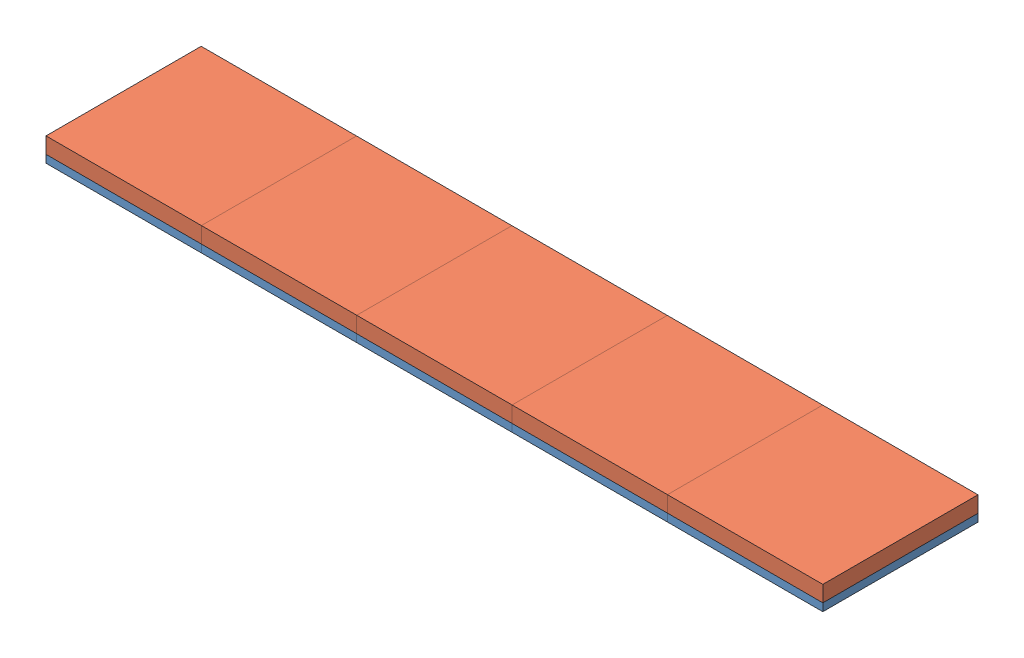
SolidWorks assembly 5_Display_Assembly, configuration Default. Lengths in mm.
Overall size (639.95 19.53 127.84).
10 component instances, 2 part files, 20 mates.
Components (placement in the parent):
- MDF-1: MDF [Default] at (-92.4493 8.8807 70.7434) size (127.99 6.35 127.84)
- 32x32_Display-1: 32x32_Display [Default] at (-92.4493 15.2307 70.7434) size (127.99 16.87 127.84)
- MDF-2: MDF [Default] at (35.5413 8.8807 70.7434) size (127.99 6.35 127.84)
- MDF-3: MDF [Default] at (163.5319 8.8807 70.7434) size (127.99 6.35 127.84)
- MDF-4: MDF [Default] at (291.5225 8.8807 70.7434) size (127.99 6.35 127.84)
- MDF-5: MDF [Default] at (419.5131 8.8807 70.7434) size (127.99 6.35 127.84)
- 32x32_Display-2: 32x32_Display [Default] at (35.5413 15.2307 70.7434) size (127.99 16.87 127.84)
- 32x32_Display-3: 32x32_Display [Default] at (163.5319 15.2307 70.7434) size (127.99 16.87 127.84)
- 32x32_Display-4: 32x32_Display [Default] at (291.5225 15.2307 70.7434) size (127.99 16.87 127.84)
- 32x32_Display-5: 32x32_Display [Default] at (419.5131 15.2307 70.7434) size (127.99 16.87 127.84)
Mates (geometry in assembly coordinates):
- Coincident1: coincident anti-aligned: plane of MDF-1 through (-92.4493 15.2307 70.7434) normal (0 1 0); plane of 32x32_Display-1 through (-92.4493 15.2307 70.7434) normal (0 -1 0)
- Coincident2: coincident aligned: plane of MDF-1 through (-92.4493 15.2307 70.7434) normal (0 0 1); plane of 32x32_Display-1 through (-92.4493 28.4133 70.7434) normal (0 0 1)
- Coincident3: coincident aligned: plane of MDF-1 through (35.5413 15.2307 70.7434) normal (1 0 0); plane of 32x32_Display-1 through (35.5413 28.4133 70.7434) normal (1 0 0)
- Coincident4: coincident aligned: plane of MDF-1 through (-92.4493 8.8807 70.7434) normal (0 -1 0); plane of MDF-2 through (35.5413 8.8807 70.7434) normal (0 -1 0)
- Coincident5: coincident aligned: plane of MDF-1 through (-92.4493 8.8807 70.7434) normal (0 -1 0); plane of MDF-3 through (163.5319 8.8807 70.7434) normal (0 -1 0)
- Coincident6: coincident aligned: plane of MDF-1 through (-92.4493 15.2307 70.7434) normal (0 0 1); plane of MDF-2 through (35.5413 15.2307 70.7434) normal (0 0 1)
- Coincident7: coincident aligned: plane of MDF-1 through (-92.4493 15.2307 70.7434) normal (0 0 1); plane of MDF-3 through (163.5319 15.2307 70.7434) normal (0 0 1)
- Coincident8: coincident anti-aligned: plane of MDF-2 through (163.5319 15.2307 70.7434) normal (1 0 0); plane of MDF-3 through (163.5319 15.2307 70.7434) normal (-1 0 0)
- Coincident10: coincident anti-aligned: plane of MDF-1 through (35.5413 15.2307 70.7434) normal (1 0 0); plane of MDF-2 through (35.5413 15.2307 70.7434) normal (-1 0 0)
- Coincident14: coincident aligned: plane of MDF-3 through (163.5319 15.2307 70.7434) normal (0 1 0); plane of MDF-4 through (291.5225 15.2307 70.7434) normal (0 1 0)
- Coincident15: coincident aligned: plane of MDF-4 through (291.5225 15.2307 70.7434) normal (0 1 0); plane of MDF-5 through (419.5131 15.2307 70.7434) normal (0 1 0)
- Coincident16: coincident aligned: plane of MDF-3 through (163.5319 15.2307 -57.0948) normal (0 0 -1); plane of MDF-4 through (291.5225 15.2307 -57.0948) normal (0 0 -1)
- Coincident17: coincident aligned: plane of MDF-4 through (291.5225 15.2307 -57.0948) normal (0 0 -1); plane of MDF-5 through (419.5131 15.2307 -57.0948) normal (0 0 -1)
- Coincident18: coincident anti-aligned: plane of MDF-3 through (291.5225 15.2307 70.7434) normal (1 0 0); plane of MDF-4 through (291.5225 15.2307 70.7434) normal (-1 0 0)
- Coincident19: coincident anti-aligned: plane of MDF-4 through (419.5131 15.2307 70.7434) normal (1 0 0); plane of MDF-5 through (419.5131 15.2307 70.7434) normal (-1 0 0)
- Coincident27: coincident aligned: plane of 32x32_Display-1 through (-92.4493 28.4133 -57.0948) normal (0 0 -1); plane of 32x32_Display-2 through (35.5413 28.4133 -57.0948) normal (0 0 -1)
- Coincident28: coincident anti-aligned: plane of 32x32_Display-1 through (35.5413 28.4133 70.7434) normal (1 0 0); plane of 32x32_Display-2 through (35.5413 28.4133 70.7434) normal (-1 0 0)
- Coincident31: coincident anti-aligned: plane of 32x32_Display-2 through (163.5319 28.4133 70.7434) normal (1 0 0); plane of 32x32_Display-3 through (163.5319 28.4133 70.7434) normal (-1 0 0)
- Coincident34: coincident anti-aligned: plane of 32x32_Display-3 through (291.5225 28.4133 70.7434) normal (1 0 0); plane of 32x32_Display-4 through (291.5225 28.4133 70.7434) normal (-1 0 0)
- Coincident36: coincident anti-aligned: plane of 32x32_Display-4 through (419.5131 28.4133 70.7434) normal (1 0 0); plane of 32x32_Display-5 through (419.5131 28.4133 70.7434) normal (-1 0 0)
